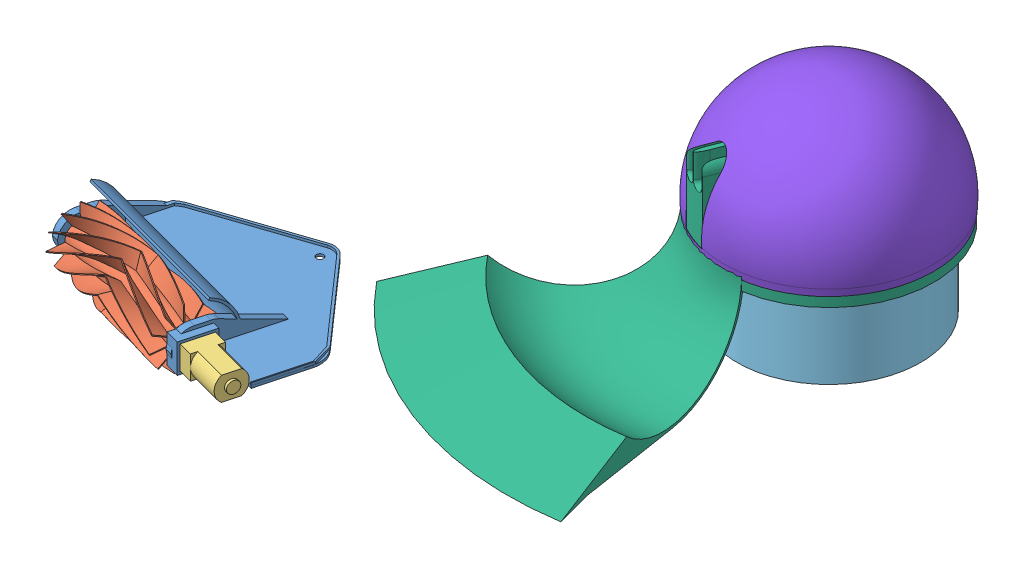
SolidWorks assembly Broomer_V2, configuration Default. Lengths in mm.
Overall size (253.39 97.2 286.46).
13 component instances, 10 part files, 9 mates.
Components (placement in the parent):
- Drone_22-1: Drone_22 [Default] at (-213.4343 33.7939 67.0318) x (0.966048 0 0.258364) z (-0.052083 0.979471 0.194742) size (95.36 80.43 40.32)
  - Drone frame22-1: Drone frame22 [Default] at (0 -41.749 12.8655) x (1 0 0) z (0 -0.979471 0.201586) size (93.99 26.74 70.08)
  - drone brush 12-1: drone brush 12 [Default] at (0 -33.899 13.8023) x (1 0 0) z (0 0.9287 0.370831) size (62.02 24.54 24.51)
  - micro dc motor-2: micro dc motor [Default] at (22.85 -33.899 13.8023) x (0 0.979471 -0.201586) z (0 0.201586 0.979471) size (12 33.91 9.85)
  - Part7563-1: Part7563 [Default] at (0 -41.5474 13.845) x (1 0 0) z (0 0.201586 0.979471) size (95.36 70.1 0) (hidden)
- Socle-1: Socle [Default] at (-184.3961 0 -24.5104) x (-0.834864 0 0.550456) z (-0.550456 0 -0.834864) size (223 97.2 212.78)
  - ruban spool-1: ruban spool [Default] at (-68.2283 53.2463 21.9215) x (0.580037 0 0.81459) z (-0.814589 -0.001264 0.580037) size (11 30 30)
  - servo holder Base-1: servo holder Base [Default] at (-70.0506 22.8363 23.2374) x (-0.546944 0 -0.837169) z (0.837169 0 -0.546944) size (76.56 53.54 76.56)
  - socle base-1: socle base [Default] at (-53.6131 0 21.3376) x (0.837169 0 -0.546944) z (0.546944 0 0.837169) size (65.04 22 76) (hidden)
  - servo holder-2: servo holder [Default] at (-65.4545 53.1463 17.1106) x (0.81459 0 -0.580037) z (0 1 0) size (178.02 134.45 74.68)
  - FS90R-1: FS90R [Default] at (-58.7617 3.3063 29.1807) x (-0.546944 0 -0.837169) z (0.837169 0 -0.546944) size (31.91 30.84 12.2)
  - FS90R-2: FS90R [Default] at (-89.9256 47.1463 1.967) x (0.81459 0 -0.580037) z (0 -1 0) size (31.91 30.84 12.2)
  - dronecover-1: dronecover [Default] at (-65.4545 36.1463 17.1106) x (0.81459 0 -0.580037) z (0 1 0) size (87.94 88.06 51.74)
Mates (geometry in assembly coordinates):
- Parallel2: parallel aligned: plane of Drone_22-1/Drone frame22-1 through (-224.6694 37.9793 109.0408) normal (0 -1 0); plane of Socle-1/servo holder Base-1 through (-125.9521 22.8363 -76.9401) normal (0 -1 0)
- Parallel3: parallel anti-aligned: plane of Drone_22-1/Drone frame22-1 through (-224.6694 37.9793 109.0408) normal (0 -1 0); plane of assembly through (0 0 0) normal (0 1 0)
- Coincident6: coincident anti-aligned: plane of Socle-1/socle base-1 through (-151.382 0 -71.8361) normal (0 -1 0); plane of assembly through (0 0 0) normal (0 1 0)
- Tangent5: tangent anti-aligned: cylinder of Socle-1/ruban spool-1 through (-140.4343 53.2463 -80.7294) axis (0.932648 0 0.360787) radius 15; plane of Part8-1
- Coincident12: coincident: plane of Drone_22-1/Drone frame22-1 through (-224.6694 38.9793 109.0408) normal (0 1 0); line of Part8-1 through (-45.6262 10.9539 218.3195) axis (0.999533 0 0.030567)
- Tangent6: tangent anti-aligned: cylinder of Socle-1/ruban spool-1 through (-140.4343 53.2463 -80.7294) axis (0.932648 0 0.360787) radius 15; plane of Part8-1
- Coincident13: coincident: point of Part8-1; circle of Socle-1/ruban spool-1
- Parallel4: parallel aligned: plane of Drone_22-1/Drone frame22-1 through (-281.9582 38.9793 52.3135) normal (-0.966048 0 -0.258364); plane of Socle-1/spool holder-1 through (-31.894 35.8601 -121.0698) normal (-0.999533 0 -0.030567)
- Parallel5: parallel anti-aligned: plane of Socle-1/servo holder Base-1 through (-125.9521 24.8363 -76.9401) normal (0 1 0); plane of servo holder-1 through (9.4017 29.2378 -70.2487) normal (0 -1 0)
